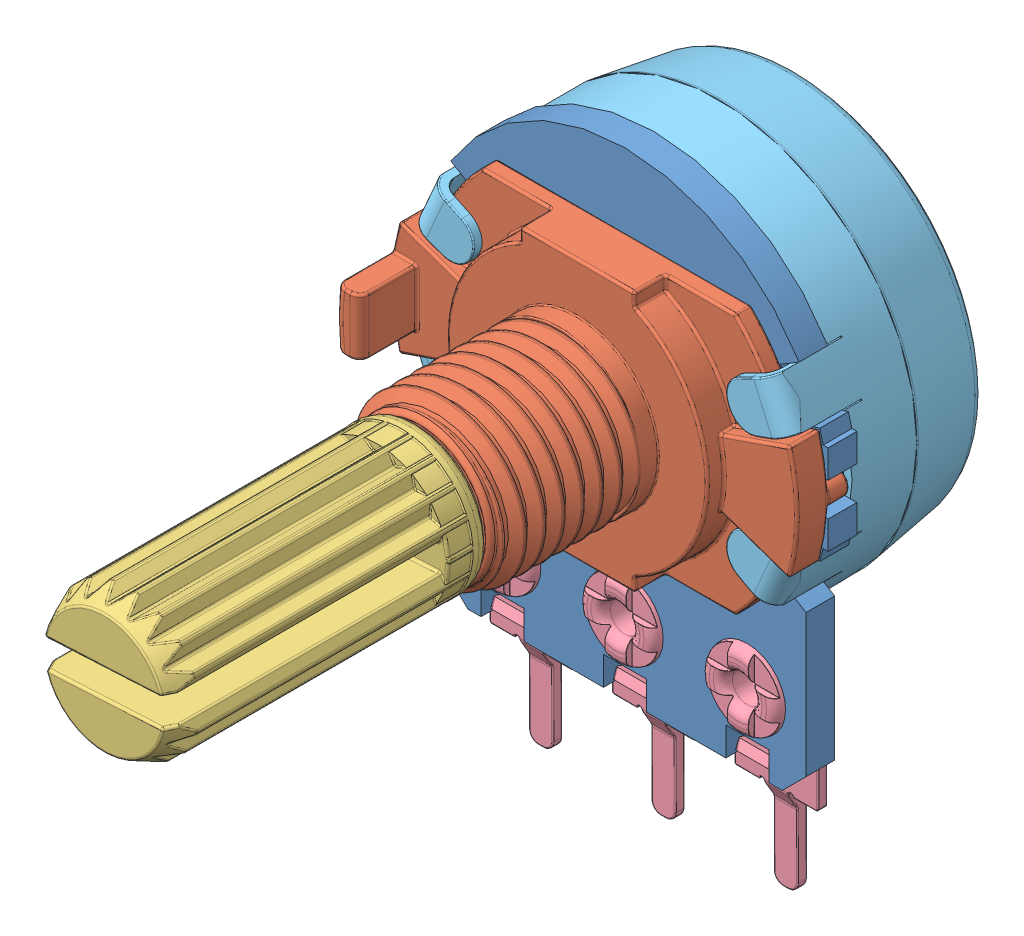
SolidWorks assembly Assem1, configuration Default. Lengths in mm.
Overall size (17.07 25.05 29.08).
8 component instances, 6 part files, 16 mates.
Components (placement in the parent):
- pcb board-1: pcb board [Default] at origin size (17 20 1.2)
- base metal-1: base metal [Default] at (0 0 1.2) size (17.07 10.9 9.8)
- rotating rod metal-1: rotating rod metal [Default] at (0 0 9.8) x (0.998576 0.053354 0) z (0 0 1) size (6 6 25.8)
- pin-1: pin [Default] at (0 -8.5 0) size (3.5 9.8 2.43)
- pin-2: pin [Default] at (5.12 -8.5 0) size (3.5 9.8 2.43)
- pin-3: pin [Default] at (-5.12 -8.5 0) size (3.5 9.8 2.43)
- sheild metal-1: sheild metal [Default] at (0 0 -6) x (-1 0 0) z (0 0 1) size (16.6 16.6 8.36)
- plastic base-1: plastic base [Default] at (0 0 -1.4) x (0.998576 0.053354 0) z (0 0 1) size (14 10.66 5.4)
Mates (geometry in assembly coordinates):
- Coincident1: coincident anti-aligned: plane of pcb board-1 through (0 0 1.2) normal (0 0 1); plane of base metal-1 through (0 0 1.2) normal (0 0 -1)
- Concentric1: concentric anti-aligned: cylinder of pcb board-1 through (0 0 1.2) axis (0 0 -1) radius 3; cylinder of base metal-1 through (0 0 0) axis (0 0 1) radius 3
- Concentric2: concentric anti-aligned: cylinder of base metal-1 through (0 0 9.8034) axis (0 0 -1) radius 2; cylinder of rotating rod metal-1 through (0 0 0) axis (0 0 1) radius 2
- Coincident2: coincident anti-aligned: plane of base metal-1 through (0 0 9.8) normal (0 0 1); plane of rotating rod metal-1 through (0 0 9.8) normal (0 0 -1)
- Concentric3: concentric anti-aligned: cylinder of pcb board-1 through (0 -8.5 0) axis (0 0 1) radius 0.9; cylinder of pin-1 through (0 -8.5 1.2) axis (0 0 -1) radius 0.9
- Coincident3: coincident anti-aligned: plane of pcb board-1 through (0 0 0) normal (0 0 -1); plane of pin-1 through (0 -8.5 0) normal (0 0 1)
- Concentric4: concentric anti-aligned: cylinder of pcb board-1 through (5.12 -8.5 0) axis (0 0 1) radius 0.9; cylinder of pin-2 through (5.12 -8.5 1.2) axis (0 0 -1) radius 0.9
- Coincident4: coincident anti-aligned: plane of pcb board-1 through (0 0 0) normal (0 0 -1); plane of pin-2 through (5.12 -8.5 0) normal (0 0 1)
- Concentric5: concentric anti-aligned: cylinder of pcb board-1 through (-5.12 -8.5 0) axis (0 0 1) radius 0.9; cylinder of pin-3 through (-5.12 -8.5 1.2) axis (0 0 -1) radius 0.9
- Coincident5: coincident anti-aligned: plane of pcb board-1 through (0 0 0) normal (0 0 -1); plane of pin-3 through (-5.12 -8.5 0) normal (0 0 1)
- Coincident6: coincident anti-aligned: plane of sheild metal-1; plane of assembly through (0 0 0) normal (0 1 0)
- Concentric6: concentric aligned: cylinder of pcb board-1 through (0 0 1.2) axis (0 0 -1) radius 8.5; cylinder of sheild metal-1 through (0 0 0) axis (0 0 -1) radius 8.3
- Coincident7: coincident anti-aligned: plane of pcb board-1 through (0 0 0) normal (0 0 -1); plane of sheild metal-1 through (0 0 0) normal (0 0 1)
- Concentric7: concentric anti-aligned: cylinder of rotating rod metal-1 through (0 0 -2.2) axis (0 0 1) radius 1; cylinder of plastic base-1 through (0 0 0) axis (0 0 -1) radius 1
- Parallel1: parallel anti-aligned: plane of rotating rod metal-1 through (-3.5199 0.3627 4.473) normal (0.053354 -0.998576 0); plane of plastic base-1 through (0.4653 5.348 -4.4) normal (-0.053354 0.998576 0)
- Coincident9: coincident anti-aligned: plane of rotating rod metal-1 through (0 0 0) normal (0 0 -1); plane of plastic base-1 through (0 0 0) normal (0 0 1)
